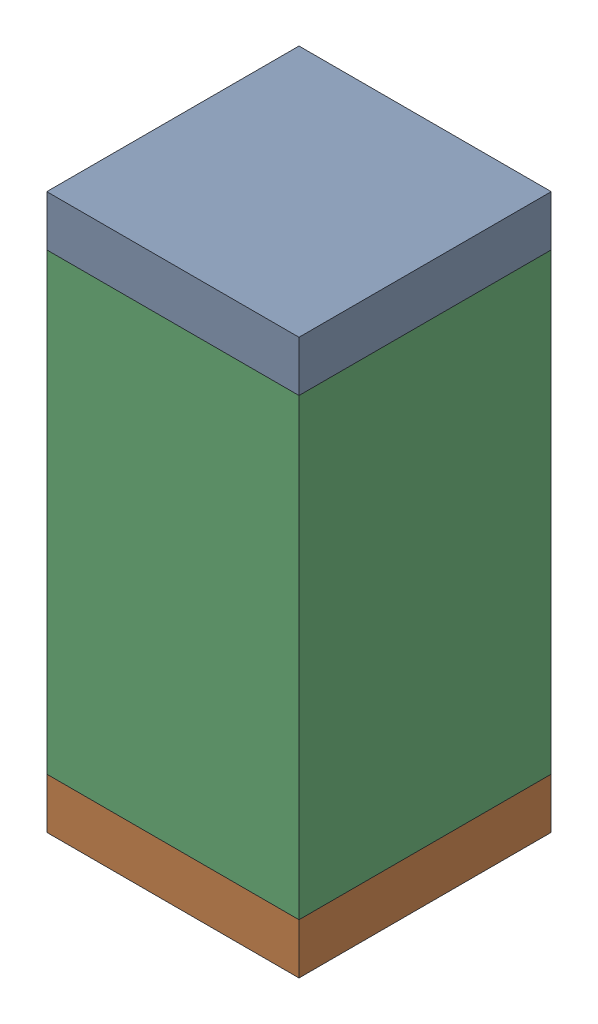
SolidWorks assembly C6, configuration Default. Lengths in mm.
Overall size (0.5 1.1 0.5).
6 component instances, 2 part files, 0 mates.
Components (placement in the parent):
- 810157360-1: 810157360 [Default] at (123.45 8.45 0) size (0.5 0.1 0.5)
  - Extruded_9-1: Extruded_9 [Default] at origin size (0.5 0.1 0.5)
- 810157360-2: 810157360 [Default] at (123.45 7.45 0) size (0.5 0.1 0.5)
  - Extruded_9-1: Extruded_9 [Default] at origin size (0.5 0.1 0.5)
- 791586336-1: 791586336 [Default] at (123.45 7.95 0) size (0.5 0.9 0.5)
  - Extruded_8-1: Extruded_8 [Default] at origin size (0.5 0.9 0.5)
